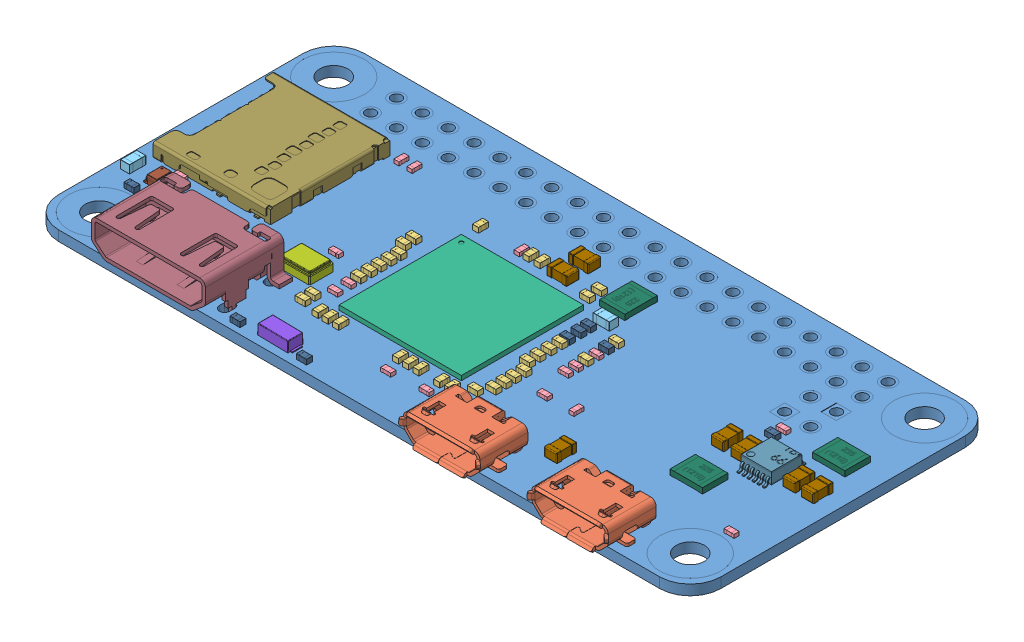
SolidWorks assembly AV_Comp_Mech_1_3_1_2_Pi_Zero, configuration Default. Lengths in mm.
Overall size (65 4.45 31.23).
81 component instances, 15 part files, 154 mates.
Components (placement in the parent):
- Raspberry_pizero_PCB-1: Raspberry_pizero_PCB [Default] at (-51.2564 20.0966 13.0542) size (65 1 30)
- Micro USB_input_female (short)-SMT-1: Micro USB_input_female (short)-SMT [Default] at (-42.3564 22.3216 26.5042) size (7.98 2.94 5.43)
- Micro USB_input_female (short)-SMT-2: Micro USB_input_female (short)-SMT [Default] at (-29.7564 22.3216 26.5042) size (7.98 2.94 5.43)
- 0204 - Capacitor-1: 0204 - Capacitor [Default] at (-62.4121 21.3466 11.2398) size (1 0.5 0.6)
- 0204 - Capacitor-2: 0204 - Capacitor [Default] at (-62.4121 21.3466 12.2528) size (1 0.5 0.6)
- 0204 - Capacitor-3: 0204 - Capacitor [Default] at (-61.8122 21.3466 13.3136) size (1 0.5 0.6)
- 0204 - Capacitor-4: 0204 - Capacitor [Default] at (-61.8122 21.3466 14.2646) size (1 0.5 0.6)
- 0204 - Capacitor-5: 0204 - Capacitor [Default] at (-61.8122 21.3466 15.241) size (1 0.5 0.6)
- 0204 - Capacitor-6: 0204 - Capacitor [Default] at (-61.8122 21.3466 16.2144) size (1 0.5 0.6)
- 0204 - Capacitor-7: 0204 - Capacitor [Default] at (-61.8122 21.3466 17.2416) size (1 0.5 0.6)
- 0204 - Capacitor-8: 0204 - Capacitor [Default] at (-62.5919 21.3466 20.9695) size (1 0.5 0.6)
- 0204 - Capacitor-9: 0204 - Capacitor [Default] at (-62.5919 21.3466 21.919) size (1 0.5 0.6)
- 0204 - Capacitor-10: 0204 - Capacitor [Default] at (-60.4584 21.3466 22.3712) x (0 0 1) z (-1 0 0) size (1 0.5 0.6)
- 0204 - Capacitor-11: 0204 - Capacitor [Default] at (-60.0807 21.3466 22.3712) x (0 0 -1) z (1 0 0) size (1 0.5 0.6)
- 0204 - Capacitor-12: 0204 - Capacitor [Default] at (-59.0466 21.3466 22.3712) x (0 0 -1) z (1 0 0) size (1 0.5 0.6)
- 0204 - Capacitor-13: 0204 - Capacitor [Default] at (-52.6496 21.3466 22.316) x (0 0 1) z (-1 0 0) size (1 0.5 0.6)
- 0204 - Capacitor-14: 0204 - Capacitor [Default] at (-52.25 21.3466 22.316) x (0 0 -1) z (1 0 0) size (1 0.5 0.6)
- 0204 - Capacitor-15: 0204 - Capacitor [Default] at (-51.2398 21.3466 22.316) x (0 0 -1) z (1 0 0) size (1 0.5 0.6)
- 0204 - Capacitor-16: 0204 - Capacitor [Default] at (-49.1841 21.3466 22.316) x (0 0 -1) z (1 0 0) size (1 0.5 0.6)
- 0204 - Capacitor-17: 0204 - Capacitor [Default] at (-48.1448 21.3466 22.316) x (0 0 -1) z (1 0 0) size (1 0.5 0.6)
- 0204 - Capacitor-18: 0204 - Capacitor [Default] at (-46.475 21.3466 21.113) size (1 0.5 0.6)
- 0204 - Capacitor-19: 0204 - Capacitor [Default] at (-45.7322 21.3466 20.0663) size (1 0.5 0.6)
- 0204 - Capacitor-20: 0204 - Capacitor [Default] at (-45.7322 21.3466 19.0675) size (1 0.5 0.6)
- 0204 - Capacitor-21: 0204 - Capacitor [Default] at (-45.7322 21.3466 18.1249) size (1 0.5 0.6)
- 0204 - Capacitor-22: 0204 - Capacitor [Default] at (-45.7322 21.3466 17.1095) size (1 0.5 0.6)
- 0204 - Capacitor-23: 0204 - Capacitor [Default] at (-46.3457 21.3466 16.1412) size (1 0.5 0.6)
- 0204 - Capacitor-24: 0204 - Capacitor [Default] at (-46.3457 21.3466 15.1229) size (1 0.5 0.6)
- 0204 - Capacitor-25: 0204 - Capacitor [Default] at (-46.3457 21.3466 14.0197) size (1 0.5 0.6)
- 0204 - Capacitor-26: 0204 - Capacitor [Default] at (-46.3457 21.3466 12.9589) size (1 0.5 0.6)
- 0204 - Capacitor-27: 0204 - Capacitor [Default] at (-43.6156 21.3466 13.1418) size (1 0.5 0.6)
- 0204 - Capacitor-28: 0204 - Capacitor [Default] at (-43.6156 21.3466 10.1424) size (1 0.5 0.6)
- 0204 - Capacitor-29: 0204 - Capacitor [Default] at (-48.9117 21.3466 7.6917) size (1 0.5 0.6)
- 0204 - Capacitor-30: 0204 - Capacitor [Default] at (-55.4926 21.3466 7.2526) x (0 0 -1) z (1 0 0) size (1 0.5 0.6)
- 0204 - Capacitor-31: 0204 - Capacitor [Default] at (-53.7932 21.3466 7.2526) x (0 0 1) z (-1 0 0) size (1 0.5 0.6)
- 0204 - Capacitor-32: 0204 - Capacitor [Default] at (-59.8477 21.3466 7.2526) x (0 0 1) z (-1 0 0) size (1 0.5 0.6)
- 0204- Resistor-15: 0204- Resistor [Default] at (-43.6109 21.4522 15.4193) x (-1 0 0) z (0 -1 0) size (0.99 0.51 0.36)
- 0204- Resistor-14: 0204- Resistor [Default] at (-43.6109 21.4522 14.4127) x (-1 0 0) z (0 -1 0) size (0.99 0.51 0.36)
- 0204- Resistor-13: 0204- Resistor [Default] at (-43.6109 21.4522 12.4047) x (-1 0 0) z (0 -1 0) size (0.99 0.51 0.36)
- 0204- Resistor-4: 0204- Resistor [Default] at (-42.6936 21.4522 18.4076) x (-1 0 0) z (0 -1 0) size (0.99 0.51 0.36)
- 0204- Resistor-5: 0204- Resistor [Default] at (-39.831 21.4522 18.1462) x (0 0 1) z (0 -1 0) size (0.99 0.51 0.36)
- 0204- Resistor-7: 0204- Resistor [Default] at (-61.8169 21.4522 19.8533) x (-1 0 0) z (0 -1 0) size (0.99 0.51 0.36)
- 0204- Resistor-8: 0204- Resistor [Default] at (-61.8169 21.4522 18.5178) x (-1 0 0) z (0 -1 0) size (0.99 0.51 0.36)
- 0204- Resistor-9: 0204- Resistor [Default] at (-79.148 21.4522 17.7279) x (-1 0 0) z (0 -1 0) size (0.99 0.51 0.36)
- 0204- Resistor-10: 0204- Resistor [Default] at (-56.0985 21.4522 7.2479) x (0 0 -1) z (0 -1 0) size (0.99 0.51 0.36)
- 0204- Resistor-11: 0204- Resistor [Default] at (-28.0827 21.4522 9.5819) x (-1 0 0) z (0 -1 0) size (0.99 0.51 0.36)
- 0204- Resistor-12: 0204- Resistor [Default] at (-21.8613 21.4522 20.9026) x (-1 0 0) z (0 -1 0) size (0.99 0.51 0.36)
- CAP-0306-1: CAP-0306 [Default] at (-45.8903 21.4966 8.7634) size (1.6 0.8 0.9)
- CAP-0306-2: CAP-0306 [Default] at (-82.0031 21.4966 19.0464) x (0 0 1) z (-1 0 0) size (1.6 0.8 0.9)
- Raspberry_pizero_BCM2835 with VC4-2: Raspberry_pizero_BCM2835 with VC4 [Default] at (-54.1608 21.5466 15.1238) x (1 0 0) z (0 0 -1) size (12 0.65 12)
- Crystal 3.4x2.4mm-1: Crystal 3.4x2.4mm [Default] at (-65.3089 21.0966 19.2633) size (3.2 1 2.4)
- 0204- Resistor-16: 0204- Resistor [Default] at (-68.4329 21.4522 5.4384) x (0 0 1) z (0 -1 0) size (0.99 0.51 0.36)
- 0204- Resistor-17: 0204- Resistor [Default] at (-69.7255 21.4522 5.4384) x (0 0 1) z (0 -1 0) size (0.99 0.51 0.36)
- 0204- Resistor-18: 0204- Resistor [Default] at (-65.0626 21.4522 16.5355) x (1 0 0) z (0 -1 0) size (0.99 0.51 0.36)
- 32,768 Khz Crystal-1: 32,768 Khz Crystal [Default] at (-60.5154 21.1428 26.5473) x (0.999848 -0.017452 0) z (0 0 1) size (3.4 1.03 1.5)
- 0805- Capacitor-1: 0805- Capacitor [Default] at (-51.9496 21.9966 5.2384) x (1 0 0) z (0 -1 0) size (2 1.25 0.9)
- 0805- Capacitor-2: 0805- Capacitor [Default] at (-51.9496 21.9966 7.3589) x (1 0 0) z (0 -1 0) size (2 1.25 0.9)
- 0805- Capacitor-3: 0805- Capacitor [Default] at (-37.009 21.9966 22.5384) x (0 0 -1) z (0 -1 0) size (2 1.25 0.9)
- 0805- Capacitor-4: 0805- Capacitor [Default] at (-29.8247 21.9966 13.3538) x (0 0 1) z (0 -1 0) size (2 1.25 0.9)
- 0805- Capacitor-5: 0805- Capacitor [Default] at (-27.9052 21.9966 13.3538) x (0 0 -1) z (0 -1 0) size (2 1.25 0.9)
- 0805- Capacitor-6: 0805- Capacitor [Default] at (-22.8003 21.9966 13.3538) x (0 0 -1) z (0 -1 0) size (2 1.25 0.9)
- 0805- Capacitor-7: 0805- Capacitor [Default] at (-20.9924 21.9966 13.3538) x (0 0 -1) z (0 -1 0) size (2 1.25 0.9)
- 0204- Resistor-19: 0204- Resistor [Default] at (-48.8769 21.4522 23.8207) x (1 0 0) z (0 -1 0) size (0.99 0.51 0.36)
- 0204- Resistor-20: 0204- Resistor [Default] at (-52.4165 21.4522 24.0419) x (1 0 0) z (0 -1 0) size (0.99 0.51 0.36)
- 0204 - Capacitor-33: 0204 - Capacitor [Default] at (-47.1199 21.3466 23.926) x (0 0 1) z (-1 0 0) size (1 0.5 0.6)
- 0204 - Capacitor Brown-34: 0204 - Capacitor Brown [Default] at (-57.5817 21.3466 26.803) size (1 0.5 0.6)
- 0204 - Capacitor Brown-35: 0204 - Capacitor Brown [Default] at (-64.0312 21.3466 26.8794) size (1 0.5 0.6)
- 0204 - Capacitor Brown-36: 0204 - Capacitor Brown [Default] at (-46.3457 21.3466 12.214) size (1 0.5 0.6)
- 0204 - Capacitor Brown-37: 0204 - Capacitor Brown [Default] at (-46.3457 21.3466 11.0963) size (1 0.5 0.6)
- 0204 - Capacitor Brown-38: 0204 - Capacitor Brown [Default] at (-46.3457 21.3466 10.1566) size (1 0.5 0.6)
- 0204 - Capacitor Brown-39: 0204 - Capacitor Brown [Default] at (-43.6156 21.3466 11.1151) size (1 0.5 0.6)
- 0204 - Capacitor Brown-40: 0204 - Capacitor Brown [Default] at (-28.0874 21.3466 10.3236) size (1 0.5 0.6)
- 0204 - Capacitor Brown-41: 0204 - Capacitor Brown [Default] at (-80.6197 21.3466 20.6997) size (1 0.5 0.6)
- 0204- Resistor-21: 0204- Resistor [Default] at (-78.9105 21.4522 21.1554) x (1 0 0) z (0 -1 0) size (0.99 0.51 0.36)
- 6-Pin SOT-1: 6-Pin SOT [Default] at (-79.714 21.0966 19.2138) x (0 0 1) z (0 1 0) size (1.5 1.84 0.95)
- micro sd molex-1: micro sd molex [Default] at (-74.7768 21.6766 -33.0961) x (0 0 1) z (0 1 0) size (11.95 11.4 1.45)
- hdmi type C-1: hdmi type C [Default] at (-71.3564 22.9466 28.6542) size (12.9 4.05 7.7)
- Voltage Regulator 3x3mm 12-Pin-1: Voltage Regulator 3x3mm 12-Pin [Default] at (-23.6842 21.0966 12.6105) x (1 0 0) z (0 1 0) size (3 4.1 1.2)
- 1210 inductor-1: 1210 inductor [Default] at (-46.4963 21.0916 6.3909) x (0 0 1) z (0 1 0) size (3.26 2.86 0.75)
- 1210 inductor-2: 1210 inductor [Default] at (-22.7405 21.0916 9.2394) x (1 0 0) z (0 1 0) size (3.26 2.86 0.75)
- 1210 inductor-3: 1210 inductor [Default] at (-28.2854 21.0916 17.6682) x (1 0 0) z (0 1 0) size (3.26 2.86 0.75)
- 0204 - Capacitor-34: 0204 - Capacitor [Default] at (-48.9117 21.3466 6.5273) size (1 0.5 0.6)
Mates (geometry in assembly coordinates):
- Coincident1: coincident anti-aligned: plane of Raspberry_pizero_PCB-1 through (-80.7564 21.0966 1.0542) normal (0 1 0); plane of Micro USB_input_female (short)-SMT-1 through (-46.4124 21.0966 24.8966) normal (0 -1 0)
- Coincident2: coincident anti-aligned: plane of Raspberry_pizero_PCB-1 through (-80.7564 21.0966 1.0542) normal (0 1 0); plane of Micro USB_input_female (short)-SMT-2 through (-33.8124 21.0966 24.8966) normal (0 -1 0)
- Coincident3: coincident aligned: plane of 0204 - Capacitor-13 through (-52.9516 21.5916 22.316) normal (0 1 0); plane of 0204 - Capacitor-14 through (-51.948 21.5916 22.316) normal (0 1 0)
- Coincident4: coincident aligned: plane of 0204 - Capacitor-14 through (-51.948 21.5916 22.316) normal (0 1 0); plane of 0204 - Capacitor-15 through (-50.9378 21.5916 22.316) normal (0 1 0)
- Coincident5: coincident aligned: plane of 0204 - Capacitor-15 through (-50.9378 21.5916 22.316) normal (0 1 0); plane of 0204 - Capacitor-16 through (-48.8821 21.5916 22.316) normal (0 1 0)
- Coincident6: coincident aligned: plane of 0204 - Capacitor-16 through (-48.8821 21.5916 22.316) normal (0 1 0); plane of 0204 - Capacitor-17 through (-47.8428 21.5916 22.316) normal (0 1 0)
- Coincident7: coincident aligned: plane of 0204 - Capacitor-17 through (-47.8428 21.5916 22.316) normal (0 1 0); plane of 0204 - Capacitor-18 through (-46.475 21.5916 21.415) normal (0 1 0)
- Coincident8: coincident aligned: plane of 0204 - Capacitor-18 through (-46.475 21.5916 21.415) normal (0 1 0); plane of 0204 - Capacitor-19 through (-45.7322 21.5916 20.3683) normal (0 1 0)
- Coincident9: coincident aligned: plane of 0204 - Capacitor-19 through (-45.7322 21.5916 20.3683) normal (0 1 0); plane of 0204 - Capacitor-20 through (-45.7322 21.5916 19.3695) normal (0 1 0)
- Coincident10: coincident aligned: plane of 0204 - Capacitor-20 through (-45.7322 21.5916 19.3695) normal (0 1 0); plane of 0204 - Capacitor-21 through (-45.7322 21.5916 18.4269) normal (0 1 0)
- Coincident11: coincident aligned: plane of 0204 - Capacitor-21 through (-45.7322 21.5916 18.4269) normal (0 1 0); plane of 0204 - Capacitor-22 through (-45.7322 21.5916 17.4115) normal (0 1 0)
- Coincident12: coincident aligned: plane of 0204 - Capacitor-22 through (-45.7322 21.5916 17.4115) normal (0 1 0); plane of 0204 - Capacitor-23 through (-46.3457 21.5916 16.4432) normal (0 1 0)
- Coincident13: coincident aligned: plane of 0204 - Capacitor-23 through (-46.3457 21.5916 16.4432) normal (0 1 0); plane of 0204 - Capacitor-24 through (-46.3457 21.5916 15.4249) normal (0 1 0)
- Coincident14: coincident aligned: plane of 0204 - Capacitor-24 through (-46.3457 21.5916 15.4249) normal (0 1 0); plane of 0204 - Capacitor-25 through (-46.3457 21.5916 14.3217) normal (0 1 0)
- Coincident15: coincident aligned: plane of 0204 - Capacitor-25 through (-46.3457 21.5916 14.3217) normal (0 1 0); plane of 0204 - Capacitor-26 through (-46.3457 21.5916 13.2609) normal (0 1 0)
- Coincident16: coincident aligned: plane of 0204 - Capacitor-26 through (-46.3457 21.5916 13.2609) normal (0 1 0); plane of 0204 - Capacitor-27 through (-43.6156 21.5916 13.4438) normal (0 1 0)
- Coincident17: coincident aligned: plane of 0204 - Capacitor-27 through (-43.6156 21.5916 13.4438) normal (0 1 0); plane of 0204 - Capacitor-28 through (-43.6156 21.5916 10.4444) normal (0 1 0)
- Coincident18: coincident aligned: plane of 0204 - Capacitor-28 through (-43.6156 21.5916 10.4444) normal (0 1 0); plane of 0204 - Capacitor-29 through (-48.9117 21.5916 7.9937) normal (0 1 0)
- Coincident19: coincident aligned: plane of 0204 - Capacitor-29 through (-48.9117 21.5916 7.9937) normal (0 1 0); plane of 0204 - Capacitor-31 through (-54.0952 21.5916 7.2526) normal (0 1 0)
- Coincident20: coincident aligned: plane of 0204 - Capacitor-30 through (-55.1906 21.5916 7.2526) normal (0 1 0); plane of 0204 - Capacitor-31 through (-54.0952 21.5916 7.2526) normal (0 1 0)
- Coincident21: coincident aligned: plane of 0204 - Capacitor-30 through (-55.1906 21.5916 7.2526) normal (0 1 0); plane of 0204 - Capacitor-32 through (-60.1497 21.5916 7.2526) normal (0 1 0)
- Coincident22: coincident aligned: plane of 0204 - Capacitor-1 through (-62.4121 21.5916 11.5418) normal (0 1 0); plane of 0204 - Capacitor-32 through (-60.1497 21.5916 7.2526) normal (0 1 0)
- Coincident23: coincident aligned: plane of 0204 - Capacitor-1 through (-62.4121 21.5916 11.5418) normal (0 1 0); plane of 0204 - Capacitor-2 through (-62.4121 21.5916 12.5548) normal (0 1 0)
- Coincident24: coincident aligned: plane of 0204 - Capacitor-2 through (-62.4121 21.5916 12.5548) normal (0 1 0); plane of 0204 - Capacitor-3 through (-61.8122 21.5916 13.6156) normal (0 1 0)
- Coincident25: coincident aligned: plane of 0204 - Capacitor-3 through (-61.8122 21.5916 13.6156) normal (0 1 0); plane of 0204 - Capacitor-4 through (-61.8122 21.5916 14.5666) normal (0 1 0)
- Coincident26: coincident aligned: plane of 0204 - Capacitor-4 through (-61.8122 21.5916 14.5666) normal (0 1 0); plane of 0204 - Capacitor-5 through (-61.8122 21.5916 15.543) normal (0 1 0)
- Coincident27: coincident aligned: plane of 0204 - Capacitor-5 through (-61.8122 21.5916 15.543) normal (0 1 0); plane of 0204 - Capacitor-6 through (-61.8122 21.5916 16.5164) normal (0 1 0)
- Coincident28: coincident aligned: plane of 0204 - Capacitor-6 through (-61.8122 21.5916 16.5164) normal (0 1 0); plane of 0204 - Capacitor-7 through (-61.8122 21.5916 17.5436) normal (0 1 0)
- Coincident29: coincident aligned: plane of 0204 - Capacitor-7 through (-61.8122 21.5916 17.5436) normal (0 1 0); plane of 0204 - Capacitor-8 through (-62.5919 21.5916 21.2715) normal (0 1 0)
- Coincident30: coincident aligned: plane of 0204 - Capacitor-8 through (-62.5919 21.5916 21.2715) normal (0 1 0); plane of 0204 - Capacitor-9 through (-62.5919 21.5916 22.221) normal (0 1 0)
- Coincident31: coincident aligned: plane of 0204 - Capacitor-9 through (-62.5919 21.5916 22.221) normal (0 1 0); plane of 0204 - Capacitor-10 through (-60.7604 21.5916 22.3712) normal (0 1 0)
- Coincident32: coincident aligned: plane of 0204 - Capacitor-10 through (-60.7604 21.5916 22.3712) normal (0 1 0); plane of 0204 - Capacitor-11 through (-59.7787 21.5916 22.3712) normal (0 1 0)
- Coincident33: coincident aligned: plane of 0204 - Capacitor-11 through (-59.7787 21.5916 22.3712) normal (0 1 0); plane of 0204 - Capacitor-12 through (-58.7446 21.5916 22.3712) normal (0 1 0)
- Coincident34: coincident anti-aligned: plane of Raspberry_pizero_PCB-1 through (-80.7564 21.0966 1.0542) normal (0 1 0); plane of 0204 - Capacitor-9 through (-62.9669 21.0966 22.219) normal (0 -1 0)
- Coincident35: coincident aligned: plane of 0204 - Capacitor-25 through (-46.8457 21.0966 14.3197) normal (-1 0 0); plane of 0204 - Capacitor-26 through (-46.8457 21.0966 13.2589) normal (-1 0 0)
- Coincident36: coincident aligned: plane of 0204 - Capacitor-24 through (-46.8457 21.0966 15.4229) normal (-1 0 0); plane of 0204 - Capacitor-25 through (-46.8457 21.0966 14.3197) normal (-1 0 0)
- Coincident37: coincident aligned: plane of 0204 - Capacitor-23 through (-46.8457 21.0966 16.4412) normal (-1 0 0); plane of 0204 - Capacitor-24 through (-46.8457 21.0966 15.4229) normal (-1 0 0)
- Coincident38: coincident aligned: plane of 0204 - Capacitor-27 through (-44.1156 21.0966 13.4418) normal (-1 0 0); plane of 0204 - Capacitor-28 through (-44.1156 21.0966 10.4424) normal (-1 0 0)
- Parallel1: parallel anti-aligned: plane of Raspberry_pizero_PCB-1 through (-80.7564 21.0966 -1.9458) normal (0 0 -1); plane of 0204 - Capacitor-30 through (-55.1926 21.0966 7.7526) normal (0 0 1)
- Coincident39: coincident aligned: plane of 0204 - Capacitor-30 through (-55.1926 21.0966 6.7526) normal (0 0 -1); plane of 0204 - Capacitor-31 through (-54.0932 21.0966 6.7526) normal (0 0 -1)
- Coincident40: coincident aligned: plane of 0204 - Capacitor-30 through (-55.1926 21.0966 6.7526) normal (0 0 -1); plane of 0204 - Capacitor-32 through (-60.1477 21.0966 6.7526) normal (0 0 -1)
- Coincident41: coincident aligned: plane of 0204 - Capacitor-1 through (-62.9121 21.0966 11.5398) normal (-1 0 0); plane of 0204 - Capacitor-2 through (-62.9121 21.0966 12.5528) normal (-1 0 0)
- Coincident42: coincident aligned: plane of 0204 - Capacitor-3 through (-62.3122 21.0966 13.6136) normal (-1 0 0); plane of 0204 - Capacitor-4 through (-62.3122 21.0966 14.5646) normal (-1 0 0)
- Coincident43: coincident aligned: plane of 0204 - Capacitor-4 through (-62.3122 21.0966 14.5646) normal (-1 0 0); plane of 0204 - Capacitor-5 through (-62.3122 21.0966 15.541) normal (-1 0 0)
- Coincident44: coincident aligned: plane of 0204 - Capacitor-5 through (-62.3122 21.0966 15.541) normal (-1 0 0); plane of 0204 - Capacitor-6 through (-62.3122 21.0966 16.5144) normal (-1 0 0)
- Coincident45: coincident aligned: plane of 0204 - Capacitor-6 through (-62.3122 21.0966 16.5144) normal (-1 0 0); plane of 0204 - Capacitor-7 through (-62.3122 21.0966 17.5416) normal (-1 0 0)
- Coincident46: coincident aligned: plane of 0204 - Capacitor-8 through (-63.0919 21.0966 21.2695) normal (-1 0 0); plane of 0204 - Capacitor-9 through (-63.0919 21.0966 22.219) normal (-1 0 0)
- Parallel2: parallel anti-aligned: plane of Raspberry_pizero_PCB-1 through (-80.7564 21.0966 28.0542) normal (0 0 1); plane of 0204 - Capacitor-10 through (-60.7584 21.0966 21.8712) normal (0 0 -1)
- Coincident48: coincident aligned: plane of 0204 - Capacitor-10 through (-60.7584 21.0966 22.8712) normal (0 0 1); plane of 0204 - Capacitor-11 through (-59.7807 21.0966 22.8712) normal (0 0 1)
- Coincident49: coincident aligned: plane of 0204 - Capacitor-11 through (-59.7807 21.0966 22.8712) normal (0 0 1); plane of 0204 - Capacitor-12 through (-58.7466 21.0966 22.8712) normal (0 0 1)
- Parallel3: parallel anti-aligned: plane of Raspberry_pizero_PCB-1 through (-80.7564 21.0966 28.0542) normal (0 0 1); plane of 0204 - Capacitor-13 through (-52.9496 21.0966 21.816) normal (0 0 -1)
- Coincident51: coincident aligned: plane of 0204 - Capacitor-13 through (-52.9496 21.0966 22.816) normal (0 0 1); plane of 0204 - Capacitor-14 through (-51.95 21.0966 22.816) normal (0 0 1)
- Coincident52: coincident aligned: plane of 0204 - Capacitor-14 through (-51.95 21.0966 22.816) normal (0 0 1); plane of 0204 - Capacitor-15 through (-50.9398 21.0966 22.816) normal (0 0 1)
- Coincident53: coincident aligned: plane of 0204 - Capacitor-15 through (-50.9398 21.0966 22.816) normal (0 0 1); plane of 0204 - Capacitor-16 through (-48.8841 21.0966 22.816) normal (0 0 1)
- Coincident54: coincident aligned: plane of 0204 - Capacitor-16 through (-48.8841 21.0966 22.816) normal (0 0 1); plane of 0204 - Capacitor-17 through (-47.8448 21.0966 22.816) normal (0 0 1)
- Parallel7: parallel anti-aligned: plane of Raspberry_pizero_PCB-1 through (-80.7564 21.0966 28.0542) normal (0 0 1); plane of CAP-0306-2 through (-82.4531 21.0966 18.2464) normal (0 0 -1)
- Parallel8: parallel aligned: plane of Raspberry_pizero_PCB-1 through (-18.7564 21.0966 25.0542) normal (1 0 0); plane of CAP-0306-1 through (-45.0903 21.0966 9.2134) normal (1 0 0)
- Coincident77: coincident aligned: plane of 0204 - Capacitor-21 through (-46.2322 21.0966 18.4249) normal (-1 0 0); plane of 0204 - Capacitor-22 through (-46.2322 21.0966 17.4095) normal (-1 0 0)
- Coincident78: coincident aligned: plane of 0204 - Capacitor-20 through (-46.2322 21.0966 19.3675) normal (-1 0 0); plane of 0204 - Capacitor-21 through (-46.2322 21.0966 18.4249) normal (-1 0 0)
- Coincident79: coincident aligned: plane of 0204 - Capacitor-19 through (-46.2322 21.0966 20.3663) normal (-1 0 0); plane of 0204 - Capacitor-20 through (-46.2322 21.0966 19.3675) normal (-1 0 0)
- Coincident80: coincident aligned: plane of Micro USB_input_female (short)-SMT-1 through (-39.2364 21.3596 23.8542) normal (0 0 -1); plane of Micro USB_input_female (short)-SMT-2 through (-26.6364 21.3596 23.8542) normal (0 0 -1)
- Distance1: distance = 41.4 mm: point of Micro USB_input_female (short)-SMT-1; plane of Raspberry_pizero_PCB-1 through (-83.7564 21.0966 25.0542) normal (-1 0 0)
- Distance3: distance = 0.8 mm aligned: plane of Micro USB_input_female (short)-SMT-1 through (-46.2564 21.0476 28.8542) normal (0 0 1); plane of Raspberry_pizero_PCB-1 through (-80.7564 21.0966 28.0542) normal (0 0 1)
- Distance4: distance = 54 mm: unknown of Micro USB_input_female (short)-SMT-2; plane of Raspberry_pizero_PCB-1 through (-83.7564 21.0966 25.0542) normal (-1 0 0)
- Coincident86: coincident anti-aligned: plane of Raspberry_pizero_PCB-1 through (-80.7564 21.0966 1.0542) normal (0 1 0); plane of Raspberry_pizero_BCM2835 with VC4-2 through (-54.1608 21.0966 15.1238) normal (0 -1 0)
- Parallel10: parallel anti-aligned: plane of Raspberry_pizero_BCM2835 with VC4-2 through (-60.1608 21.0966 9.1238) normal (0 0 -1); plane of Raspberry_pizero_PCB-1 through (-80.7564 21.0966 28.0542) normal (0 0 1)
- Coincident88: coincident anti-aligned: plane of Raspberry_pizero_PCB-1 through (-80.7564 21.0966 1.0542) normal (0 1 0); plane of CAP-0306-1 through (-45.2653 21.0966 9.2134) normal (0 -1 0)
- Coincident89: coincident aligned: plane of 0204- Resistor-7 through (-61.5248 21.0966 19.5993) normal (0 -1 0); plane of 0204- Resistor-8 through (-61.5248 21.0966 18.2638) normal (0 -1 0)
- Coincident90: coincident anti-aligned: plane of Raspberry_pizero_PCB-1 through (-80.7564 21.0966 1.0542) normal (0 1 0); plane of 0204- Resistor-8 through (-61.5248 21.0966 18.2638) normal (0 -1 0)
- Parallel11: parallel aligned: plane of Raspberry_pizero_PCB-1 through (-80.7564 21.0966 28.0542) normal (0 0 1); plane of 0204 - Capacitor-7 through (-61.8122 21.1016 17.8406) normal (0 0 1)
- Coincident92: coincident aligned: plane of 0204 - Capacitor-7 through (-62.3122 21.0966 17.5416) normal (-1 0 0); plane of 0204- Resistor-8 through (-62.3122 21.0966 18.2638) normal (-1 0 0)
- Coincident93: coincident aligned: plane of 0204- Resistor-7 through (-62.3122 21.0966 19.5993) normal (-1 0 0); plane of 0204- Resistor-8 through (-62.3122 21.0966 18.2638) normal (-1 0 0)
- Coincident94: coincident aligned: plane of 0204 - Capacitor-30 through (-55.1926 21.0966 6.7526) normal (0 0 -1); plane of 0204- Resistor-10 through (-55.8445 21.0966 6.7526) normal (0 0 -1)
- Coincident95: coincident anti-aligned: plane of Raspberry_pizero_PCB-1 through (-80.7564 21.0966 1.0542) normal (0 1 0); plane of 0204- Resistor-10 through (-55.8445 21.0966 6.9558) normal (0 -1 0)
- Coincident96: coincident aligned: plane of 0204- Resistor-14 through (-43.903 21.0966 14.1587) normal (0 -1 0); plane of 0204- Resistor-13 through (-43.903 21.0966 12.1507) normal (0 -1 0)
- Coincident97: coincident aligned: plane of 0204- Resistor-15 through (-43.903 21.0966 15.1653) normal (0 -1 0); plane of 0204- Resistor-14 through (-43.903 21.0966 14.1587) normal (0 -1 0)
- Coincident98: coincident aligned: plane of 0204- Resistor-15 through (-43.903 21.0966 15.1653) normal (0 -1 0); plane of 0204- Resistor-4 through (-42.9857 21.0966 18.1536) normal (0 -1 0)
- Coincident99: coincident anti-aligned: plane of Raspberry_pizero_PCB-1 through (-80.7564 21.0966 1.0542) normal (0 1 0); plane of 0204- Resistor-15 through (-43.903 21.0966 15.1653) normal (0 -1 0)
- Coincident101: coincident aligned: plane of 0204- Resistor-5 through (-40.085 21.0966 18.4383) normal (0 -1 0); plane of 0204- Resistor-11 through (-27.7906 21.0966 9.3279) normal (0 -1 0)
- Coincident102: coincident aligned: plane of 0204- Resistor-11 through (-27.7906 21.0966 9.3279) normal (0 -1 0); plane of 0204- Resistor-12 through (-21.5692 21.0966 20.6486) normal (0 -1 0)
- Coincident103: coincident anti-aligned: plane of Raspberry_pizero_PCB-1 through (-80.7564 21.0966 1.0542) normal (0 1 0); plane of Crystal 3.4x2.4mm-1 through (-65.3089 21.0966 19.2633) normal (0 -1 0)
- Parallel12: parallel aligned: plane of Raspberry_pizero_PCB-1 through (-80.7564 21.0966 28.0542) normal (0 0 1); plane of Crystal 3.4x2.4mm-1 through (-66.9089 21.7966 20.4633) normal (0 0 1)
- Coincident104: coincident anti-aligned: plane of Raspberry_pizero_PCB-1 through (-80.7564 21.0966 1.0542) normal (0 1 0); plane of 0204- Resistor-9 through (-78.8559 21.0966 17.4739) normal (0 -1 0)
- Parallel13: parallel aligned: plane of Raspberry_pizero_PCB-1 through (-80.7564 21.0966 28.0542) normal (0 0 1); plane of 0204- Resistor-9 through (-78.2985 21.4532 17.9829) normal (0 0 1)
- Coincident105: coincident anti-aligned: plane of Raspberry_pizero_PCB-1 through (-80.7564 21.0966 1.0542) normal (0 1 0); plane of CAP-0306-2 through (-82.4531 21.0966 19.6714) normal (0 -1 0)
- Coincident106: coincident aligned: plane of 0204 - Capacitor-28 through (-43.1156 21.0966 10.4424) normal (1 0 0); plane of 0204- Resistor-13 through (-43.1156 21.0966 12.1507) normal (1 0 0)
- Coincident107: coincident aligned: plane of 0204 - Capacitor-27 through (-43.1156 21.0966 13.4418) normal (1 0 0); plane of 0204- Resistor-14 through (-43.1156 21.0966 14.1587) normal (1 0 0)
- Parallel14: parallel aligned: plane of Raspberry_pizero_PCB-1 through (-80.7564 21.0966 28.0542) normal (0 0 1); plane of 0204- Resistor-14 through (-42.7614 21.4532 14.6677) normal (0 0 1)
- Coincident110: coincident aligned: plane of 0204- Resistor-15 through (-43.1156 21.0966 15.1653) normal (1 0 0); plane of 0204- Resistor-14 through (-43.1156 21.0966 14.1587) normal (1 0 0)
- Parallel15: parallel aligned: plane of 0204- Resistor-15 through (-43.1156 21.0966 15.1653) normal (1 0 0); plane of 0204- Resistor-4 through (-42.1983 21.0966 18.1536) normal (1 0 0)
- Parallel16: parallel aligned: plane of Raspberry_pizero_PCB-1 through (-80.7564 21.0966 28.0542) normal (0 0 1); plane of 0204- Resistor-5 through (-40.085 21.0966 18.6415) normal (0 0 1)
- Coincident112: coincident anti-aligned: plane of Raspberry_pizero_PCB-1 through (-80.7564 21.0966 1.0542) normal (0 1 0); plane of 0204- Resistor-5 through (-40.085 21.0966 18.4383) normal (0 -1 0)
- Parallel17: parallel aligned: plane of Raspberry_pizero_PCB-1 through (-18.7564 21.0966 25.0542) normal (1 0 0); plane of 0204- Resistor-12 through (-21.366 21.0966 20.6486) normal (1 0 0)
- Parallel18: parallel aligned: plane of 0204- Resistor-11 through (-27.5874 21.0966 9.3279) normal (1 0 0); plane of 0204- Resistor-12 through (-21.366 21.0966 20.6486) normal (1 0 0)
- Coincident115: coincident anti-aligned: plane of Raspberry_pizero_PCB-1 through (-80.7564 21.0966 1.0542) normal (0 1 0); plane of 0204- Resistor-16 through (-68.6869 21.0966 5.1463) normal (0 -1 0)
- Coincident116: coincident aligned: plane of 0204- Resistor-16 through (-68.6879 21.4532 4.5889) normal (0 1 0); plane of 0204- Resistor-17 through (-69.9805 21.4532 4.5889) normal (0 1 0)
- Coincident117: coincident aligned: plane of 0204- Resistor-17 through (-69.9805 21.4532 4.5889) normal (0 1 0); plane of 0204- Resistor-18 through (-65.9121 21.4532 16.7905) normal (0 1 0)
- Coincident118: coincident aligned: plane of 0204- Resistor-16 through (-68.6869 21.0966 5.9337) normal (0 0 1); plane of 0204- Resistor-17 through (-69.9795 21.0966 5.9337) normal (0 0 1)
- Parallel19: parallel anti-aligned: plane of Raspberry_pizero_PCB-1 through (-80.7564 21.0966 -1.9458) normal (0 0 -1); plane of 0204- Resistor-17 through (-69.9795 21.0966 5.9337) normal (0 0 1)
- Parallel20: parallel aligned: plane of Raspberry_pizero_PCB-1 through (-80.7564 21.0966 28.0542) normal (0 0 1); plane of 0204- Resistor-18 through (-65.9121 21.4532 16.7905) normal (0 0 1)
- Coincident120: coincident anti-aligned: plane of Raspberry_pizero_PCB-1 through (-80.7564 21.0966 1.0542) normal (0 1 0); plane of 32,768 Khz Crystal-1 through (-59.5156 21.0966 27.0473) normal (0 -1 0)
- Coincident121: coincident anti-aligned: plane of Raspberry_pizero_PCB-1 through (-80.7564 21.0966 1.0542) normal (0 1 0); plane of 0805- Capacitor-1 through (-52.9496 21.0966 5.8634) normal (0 -1 0)
- Coincident122: coincident anti-aligned: plane of Raspberry_pizero_PCB-1 through (-80.7564 21.0966 1.0542) normal (0 1 0); plane of 0805- Capacitor-2 through (-52.9496 21.0966 7.9839) normal (0 -1 0)
- Coincident123: coincident anti-aligned: plane of Raspberry_pizero_PCB-1 through (-80.7564 21.0966 1.0542) normal (0 1 0); plane of 0805- Capacitor-3 through (-37.634 21.0966 21.5384) normal (0 -1 0)
- Coincident124: coincident anti-aligned: plane of Raspberry_pizero_PCB-1 through (-80.7564 21.0966 1.0542) normal (0 1 0); plane of 0805- Capacitor-4 through (-30.4497 21.0966 12.3538) normal (0 -1 0)
- Coincident125: coincident anti-aligned: plane of Raspberry_pizero_PCB-1 through (-80.7564 21.0966 1.0542) normal (0 1 0); plane of 0805- Capacitor-5 through (-27.2802 21.0966 14.3538) normal (0 -1 0)
- Parallel21: parallel anti-aligned: plane of Raspberry_pizero_PCB-1 through (-80.7564 21.0966 28.0542) normal (0 0 1); plane of 0805- Capacitor-4 through (-29.8247 21.9966 12.3538) normal (0 0 -1)
- Coincident126: coincident aligned: plane of 0805- Capacitor-4 through (-29.8247 21.9966 14.3538) normal (0 0 1); plane of 0805- Capacitor-5 through (-27.9052 21.9966 14.3538) normal (0 0 1)
- Coincident127: coincident anti-aligned: plane of Raspberry_pizero_PCB-1 through (-80.7564 21.0966 1.0542) normal (0 1 0); plane of 0805- Capacitor-6 through (-22.1753 21.0966 14.3538) normal (0 -1 0)
- Coincident128: coincident anti-aligned: plane of Raspberry_pizero_PCB-1 through (-80.7564 21.0966 1.0542) normal (0 1 0); plane of 0805- Capacitor-7 through (-20.3674 21.0966 14.3538) normal (0 -1 0)
- Coincident129: coincident aligned: plane of 0805- Capacitor-5 through (-27.9052 21.9966 14.3538) normal (0 0 1); plane of 0805- Capacitor-6 through (-22.8003 21.9966 14.3538) normal (0 0 1)
- Coincident130: coincident aligned: plane of 0805- Capacitor-6 through (-22.8003 21.9966 14.3538) normal (0 0 1); plane of 0805- Capacitor-7 through (-20.9924 21.9966 14.3538) normal (0 0 1)
- Parallel22: parallel anti-aligned: plane of Raspberry_pizero_PCB-1 through (-80.7564 21.0966 28.0542) normal (0 0 1); plane of 0805- Capacitor-3 through (-37.009 21.9966 21.5384) normal (0 0 -1)
- Coincident131: coincident aligned: plane of 0805- Capacitor-1 through (-50.9496 21.9966 5.2384) normal (1 0 0); plane of 0805- Capacitor-2 through (-50.9496 21.9966 7.3589) normal (1 0 0)
- Parallel23: parallel anti-aligned: plane of Raspberry_pizero_PCB-1 through (-80.7564 21.0966 28.0542) normal (0 0 1); plane of 6-Pin SOT-1 through (-80.214 22.0466 18.4638) normal (0 0 -1)
- Coincident134: coincident anti-aligned: plane of Raspberry_pizero_PCB-1 through (-80.7564 21.0966 1.0542) normal (0 1 0); plane of 6-Pin SOT-1 through (-80.434 21.0966 19.8263) normal (0 -1 0)
- Coincident135: coincident anti-aligned: plane of Raspberry_pizero_PCB-1 through (-80.7564 21.0966 1.0542) normal (0 1 0); plane of micro sd molex-1 through (-71.1444 21.0966 16.7043) normal (0 -1 0)
- Parallel24: parallel aligned: plane of Raspberry_pizero_PCB-1 through (-80.7564 21.0966 -1.9458) normal (0 0 -1); plane of micro sd molex-1 through (-84.5393 22.448 5.3989) normal (0 0 -1)
- Coincident141: coincident anti-aligned: plane of Raspberry_pizero_PCB-1 through (-80.7564 21.0966 1.0542) normal (0 1 0); plane of hdmi type C-1 through (-77.8064 21.0966 20.9542) normal (0 -1 0)
- Distance5: distance = 12.4 mm: unknown of hdmi type C-1; plane of Raspberry_pizero_PCB-1 through (-83.7564 21.0966 25.0542) normal (-1 0 0)
- Distance6: distance = 17.2 mm: unknown of micro sd molex-1; plane of Raspberry_pizero_PCB-1 through (-80.7564 21.0966 28.0542) normal (0 0 1)
- Parallel25: parallel aligned: plane of Raspberry_pizero_PCB-1 through (-80.7564 21.0966 28.0542) normal (0 0 1); plane of hdmi type C-1 through (-71.3564 22.9466 28.6542) normal (0 0 1)
- Distance7: distance = 0.6 mm aligned: plane of hdmi type C-1 through (-71.3564 22.9466 28.6542) normal (0 0 1); plane of Raspberry_pizero_PCB-1 through (-80.7564 21.0966 28.0542) normal (0 0 1)
- Coincident142: coincident anti-aligned: plane of Raspberry_pizero_PCB-1 through (-80.7564 21.0966 1.0542) normal (0 1 0); plane of 0204 - Capacitor Brown-34 through (-57.9567 21.0966 27.103) normal (0 -1 0)
- Coincident143: coincident aligned: plane of 0204 - Capacitor Brown-34 through (-57.5817 21.5916 27.105) normal (0 1 0); plane of 0204 - Capacitor Brown-35 through (-64.0312 21.5916 27.1814) normal (0 1 0)
- Coincident144: coincident aligned: plane of 0204 - Capacitor-18 through (-46.475 21.5916 21.415) normal (0 1 0); plane of 0204 - Capacitor-33 through (-47.4219 21.5916 23.926) normal (0 1 0)
- Parallel26: parallel anti-aligned: plane of Raspberry_pizero_PCB-1 through (-80.7564 21.0966 28.0542) normal (0 0 1); plane of 0204 - Capacitor-33 through (-47.4199 21.0966 23.426) normal (0 0 -1)
- Coincident146: coincident anti-aligned: plane of Raspberry_pizero_PCB-1 through (-80.7564 21.0966 1.0542) normal (0 1 0); plane of 0204- Resistor-19 through (-48.5848 21.0966 24.0747) normal (0 -1 0)
- Coincident147: coincident anti-aligned: plane of Raspberry_pizero_PCB-1 through (-80.7564 21.0966 1.0542) normal (0 1 0); plane of 0204- Resistor-20 through (-52.1244 21.0966 24.2959) normal (0 -1 0)
- Coincident148: coincident anti-aligned: plane of Raspberry_pizero_PCB-1 through (-80.7564 21.0966 1.0542) normal (0 1 0); plane of 0204- Resistor-21 through (-79.2026 21.0966 21.4094) normal (0 -1 0)
- Coincident149: coincident anti-aligned: plane of Raspberry_pizero_PCB-1 through (-80.7564 21.0966 1.0542) normal (0 1 0); plane of 0204 - Capacitor Brown-41 through (-80.9947 21.0966 20.9997) normal (0 -1 0)
- Parallel27: parallel aligned: plane of Raspberry_pizero_PCB-1 through (-80.7564 21.0966 28.0542) normal (0 0 1); plane of 0204- Resistor-21 through (-78.9105 21.4522 21.4094) normal (0 0 1)
- Parallel28: parallel aligned: plane of Raspberry_pizero_PCB-1 through (-80.7564 21.0966 28.0542) normal (0 0 1); plane of 0204 - Capacitor Brown-41 through (-80.6197 21.1016 21.2987) normal (0 0 1)
- Parallel29: parallel aligned: plane of 0204- Resistor-19 through (-49.7264 21.4532 24.0757) normal (0 0 1); plane of 0204- Resistor-20 through (-53.266 21.4532 24.2969) normal (0 0 1)
- Coincident152: coincident aligned: plane of 0204 - Capacitor Brown-34 through (-57.5817 21.5916 27.105) normal (0 1 0); plane of 0204 - Capacitor Brown-39 through (-43.6156 21.5916 11.4171) normal (0 1 0)
- Coincident153: coincident aligned: plane of 0204 - Capacitor Brown-36 through (-46.3457 21.5916 12.516) normal (0 1 0); plane of 0204 - Capacitor Brown-39 through (-43.6156 21.5916 11.4171) normal (0 1 0)
- Coincident154: coincident aligned: plane of 0204 - Capacitor Brown-36 through (-46.3457 21.5916 12.516) normal (0 1 0); plane of 0204 - Capacitor Brown-37 through (-46.3457 21.5916 11.3983) normal (0 1 0)
- Coincident155: coincident aligned: plane of 0204 - Capacitor Brown-37 through (-46.3457 21.5916 11.3983) normal (0 1 0); plane of 0204 - Capacitor Brown-38 through (-46.3457 21.5916 10.4586) normal (0 1 0)
- Coincident156: coincident aligned: plane of 0204 - Capacitor-26 through (-45.8457 21.0966 13.2589) normal (1 0 0); plane of 0204 - Capacitor Brown-36 through (-45.8457 21.0966 12.514) normal (1 0 0)
- Coincident157: coincident aligned: plane of 0204 - Capacitor Brown-36 through (-45.8457 21.0966 12.514) normal (1 0 0); plane of 0204 - Capacitor Brown-37 through (-45.8457 21.0966 11.3963) normal (1 0 0)
- Coincident158: coincident aligned: plane of 0204 - Capacitor Brown-37 through (-45.8457 21.0966 11.3963) normal (1 0 0); plane of 0204 - Capacitor Brown-38 through (-45.8457 21.0966 10.4566) normal (1 0 0)
- Coincident159: coincident aligned: plane of 0204 - Capacitor-28 through (-43.1156 21.0966 10.4424) normal (1 0 0); plane of 0204 - Capacitor Brown-39 through (-43.1156 21.0966 11.4151) normal (1 0 0)
- Coincident160: coincident aligned: plane of 0204 - Capacitor Brown-39 through (-43.6156 21.5916 11.4171) normal (0 1 0); plane of 0204 - Capacitor Brown-40 through (-28.0874 21.5916 10.6256) normal (0 1 0)
- Coincident161: coincident aligned: plane of 0204- Resistor-11 through (-27.5874 21.0966 9.3279) normal (1 0 0); plane of 0204 - Capacitor Brown-40 through (-27.5874 21.0966 10.6236) normal (1 0 0)
- Coincident163: coincident anti-aligned: plane of Raspberry_pizero_PCB-1 through (-80.7564 21.0966 1.0542) normal (0 1 0); plane of Voltage Regulator 3x3mm 12-Pin-1 through (-24.1342 21.0966 11.3118) normal (0 -1 0)
- Parallel30: parallel aligned: plane of Raspberry_pizero_PCB-1 through (-18.7564 21.0966 25.0542) normal (1 0 0); plane of Voltage Regulator 3x3mm 12-Pin-1 through (-23.9842 22.2966 11.8605) normal (1 0 0)
- Coincident165: coincident anti-aligned: plane of Raspberry_pizero_PCB-1 through (-80.7564 21.0966 1.0542) normal (0 1 0); line of 1210 inductor-2 through (-21.1405 21.0966 7.9944) axis (0 0 1)
- Coincident166: coincident aligned: plane of 1210 inductor-3 through (-28.2854 21.6416 16.4182) normal (0 1 0); plane of 1210 inductor-2 through (-22.7405 21.6416 7.9894) normal (0 1 0)
- Coincident167: coincident aligned: plane of 0204 - Capacitor-29 through (-48.9117 21.5916 7.9937) normal (0 1 0); plane of 0204 - Capacitor-34 through (-48.9117 21.5916 6.8293) normal (0 1 0)
- Coincident168: coincident aligned: plane of 0204 - Capacitor-29 through (-49.4117 21.0966 7.9917) normal (-1 0 0); plane of 0204 - Capacitor-34 through (-49.4117 21.0966 6.8273) normal (-1 0 0)
- Coincident169: coincident aligned: plane of 1210 inductor-1 through (-45.2463 21.6416 6.3909) normal (0 1 0); plane of 1210 inductor-2 through (-22.7405 21.6416 7.9894) normal (0 1 0)
- Parallel31: parallel aligned: plane of Raspberry_pizero_PCB-1 through (-18.7564 21.0966 25.0542) normal (1 0 0); plane of 1210 inductor-2 through (-21.1405 21.3666 10.4894) normal (1 0 0)
- Parallel32: parallel aligned: plane of Raspberry_pizero_PCB-1 through (-18.7564 21.0966 25.0542) normal (1 0 0); plane of 1210 inductor-3 through (-26.6854 21.3666 18.9182) normal (1 0 0)
- Parallel33: parallel aligned: plane of Raspberry_pizero_PCB-1 through (-18.7564 21.0966 25.0542) normal (1 0 0); plane of 1210 inductor-1 through (-45.2468 21.3666 6.3909) normal (1 0 0)
